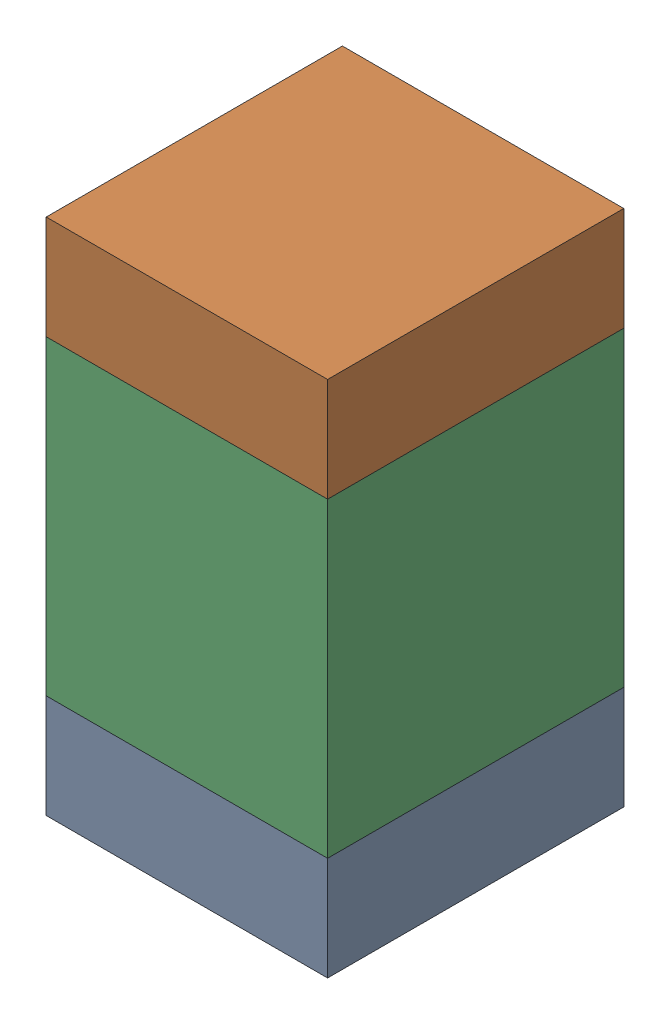
SolidWorks assembly C2-1, configuration Default. Lengths in mm.
Overall size (0.95 1.75 1).
6 component instances, 2 part files, 0 mates.
Components (placement in the parent):
- 959208664-1-1: 959208664-1 [Default] at (140.8925 85.698 0) size (0.95 0.35 1)
  - Extruded-45-1: Extruded-45 [Default] at origin size (0.95 0.35 1)
- 959208664-1-2: 959208664-1 [Default] at (140.8925 87.098 0) size (0.95 0.35 1)
  - Extruded-45-1: Extruded-45 [Default] at origin size (0.95 0.35 1)
- 959208528-1-1: 959208528-1 [Default] at (140.8925 86.398 0) size (0.95 1.05 1)
  - Extruded-46-1: Extruded-46 [Default] at origin size (0.95 1.05 1)
